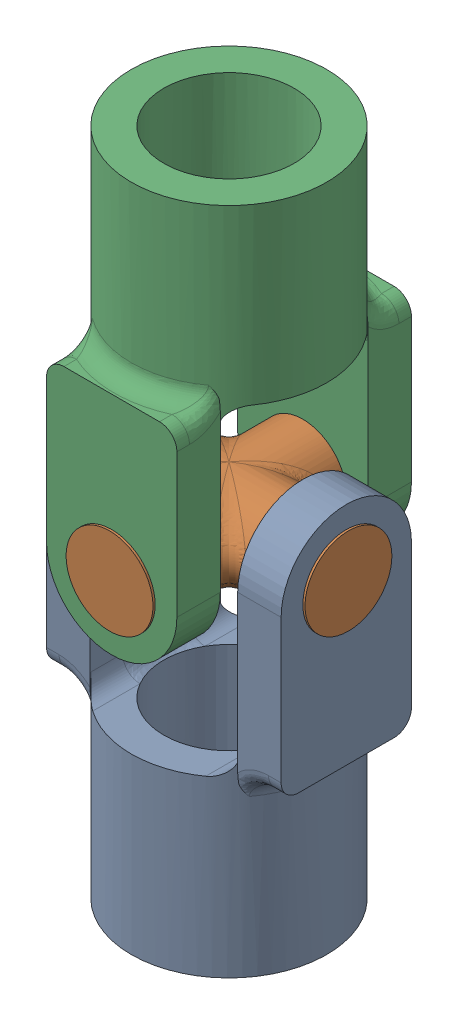
SolidWorks assembly 230023, configuration Default. Lengths in mm.
Overall size (34.92 97.79 34.92).
3 component instances, 2 part files, 4 mates.
Components (placement in the parent):
- 230018-1: 230018 [Default] at origin size (34.29 58.42 28.57)
- 230019-1: 230019 [Default] at (0 23.495 0) size (34.92 12.7 34.92)
- 230018-2: 230018 [Default] at (0 46.99 0) x (0 0 -1) z (-1 0 0) size (34.29 58.42 28.57)
Mates (geometry in assembly coordinates):
- Concentric1: concentric anti-aligned: cylinder of U-Joint Housing-1 through (-17.145 23.495 0) axis (1 0 0) radius 6.35; cylinder of U-Joint Cross-1 through (17.4625 23.495 0) axis (-1 0 0) radius 6.35
- Width1: width anti-aligned: plane of U-Joint Cross-1 through (17.4625 23.495 0) normal (1 0 0); plane of U-Joint Cross-1 through (-17.4625 23.495 0) normal (-1 0 0); plane of U-Joint Housing-1 through (-17.145 0 9.525) normal (-1 0 0); plane of U-Joint Housing-1 through (17.145 0 9.525) normal (1 0 0)
- Concentric2: concentric aligned: cylinder of U-Joint Cross-1 through (0 23.495 17.4625) axis (0 0 -1) radius 6.35; cylinder of U-Joint Housing-2 through (0 23.495 17.145) axis (0 0 -1) radius 6.35
- Width2: width anti-aligned: plane of U-Joint Housing-2 through (-9.525 46.99 17.145) normal (0 0 1); plane of U-Joint Housing-2 through (-9.525 46.99 -17.145) normal (0 0 -1); plane of U-Joint Cross-1 through (0 23.495 -17.4625) normal (0 0 -1); plane of U-Joint Cross-1 through (0 23.495 17.4625) normal (0 0 1)
